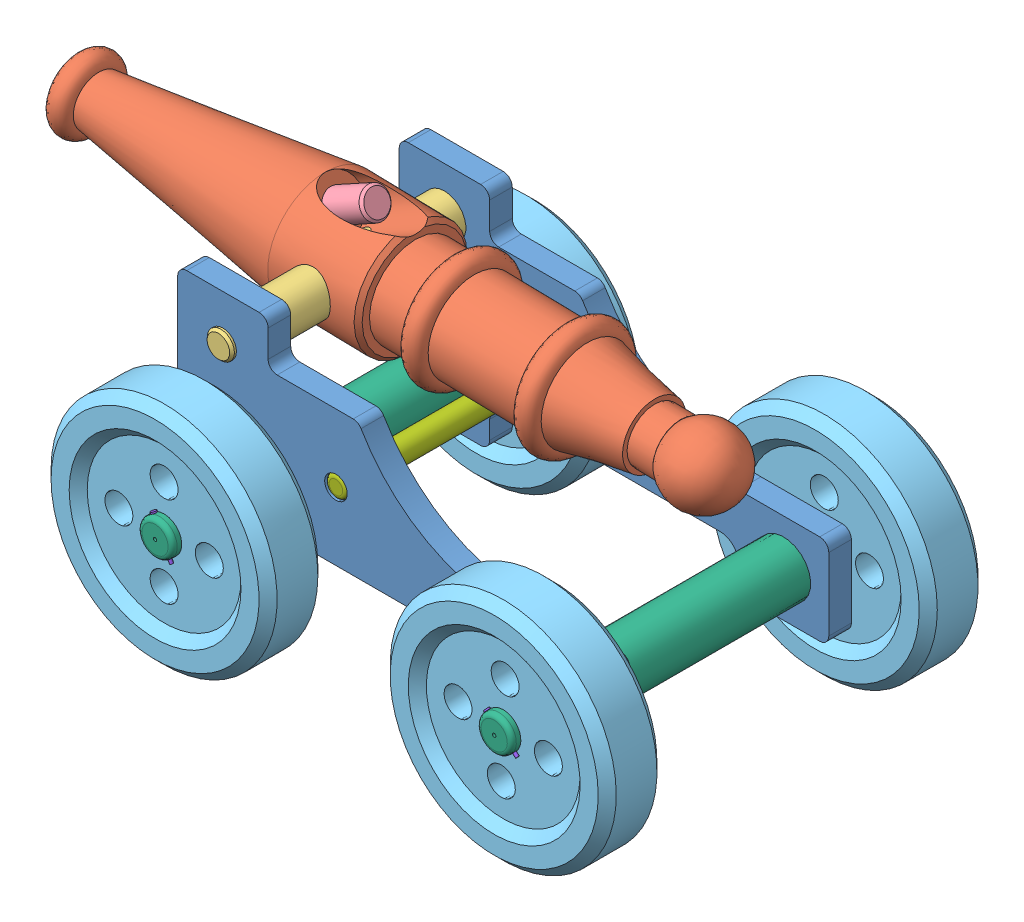
SolidWorks assembly Assem1, configuration Varsayılan. Lengths in mm.
Overall size (1654.34 725.8 840).
16 component instances, 8 part files, 31 mates.
Components (placement in the parent):
- yan parçalar-1: yan parçalar [Varsayılan] at (-537.6086 -308.226 925) size (950 500 50)
- yan parçalar-2: yan parçalar [Varsayılan] at (-537.6086 -308.226 435) size (950 500 50)
- top-1: top [Varsayılan] at (-331.2218 -35.2403 660) x (0.999785 -0.020755 0) z (0 0 1) size (1470 298.28 279.51)
- destek parça 2-1: destek parça 2 [Varsayılan] at (-437.6086 61.774 425) x (0 0 1) z (-1 0 0) size (560 95 95)
- çivi 2-1: çivi 2 [Varsayılan] at (-509.6694 189.1829 637.3824) x (0.876216 0.481918 0) z (-0.34062 0.619311 0.707412) size (318 64 64)
- teker-1: teker [Varsayılan] at (312.3914 -67.237 -513.471) x (0 0 -1) z (-1 0 0) size (130 500 500)
- teker-2: teker [Varsayılan] at (-437.6086 -349.215 -513.471) x (0 0 -1) z (1 0 0) size (130 500 500)
- teker-3: teker [Varsayılan] at (-437.6086 -349.215 196.529) x (0 0 -1) z (1 0 0) size (130 500 500)
- teker-4: teker [Varsayılan] at (306.4081 -349.088 196.529) x (0 0 -1) z (0.999099 -0.042438 0) size (130 500 500)
- destek parça-1: destek parça [Varsayılan] at (294.464 -193.0498 1173.5551) x (0 0 -1) z (-0.646111 -0.763244 0) size (840 120 120)
- destek parça-2: destek parça [Varsayılan] at (-427.1025 -229.2338 1173.5551) x (0 0 -1) z (0.894391 0.447286 0) size (840 120 120)
- ara vida-1: ara vida [Varsayılan] at (-187.6086 -83.226 975) x (0 0 -1) z (1 0 0) size (540 50 50)
- çivi-1: çivi [Varsayılan] at (-456.4668 -170.6977 1104.0005) x (0.012037 0.00602 0.999909) z (0.89431 0.447246 -0.013459) size (12 90 12)
- çivi-2: çivi [Varsayılan] at (282.4363 -178.6073 305.0423) x (-0.350187 -0.413672 -0.840383) z (-0.542981 -0.641417 0.541992) size (12 90 12)
- çivi-3: çivi [Varsayılan] at (-454.4406 -169.6843 294.4119) x (-0.325669 -0.162868 0.931351) z (0.832991 0.41658 0.364124) size (12 90 12)
- çivi-4: çivi [Varsayılan] at (283.9475 -176.8222 1107.8221) x (-0.602044 -0.711188 0.362979) z (0.234525 0.277042 0.931797) size (12 90 12)
Mates (geometry in assembly coordinates):
- Eş Merkezli1: concentric anti-aligned: cylinder of top-1 through (-437.6086 91.774 520.2468) axis (0 0 1) radius 47.5; cylinder of destek parça 2-1 through (-437.6086 91.774 425) axis (0 0 -1) radius 47.5
- Çakışık1: coincident anti-aligned: plane of yan parçalar-1 through (-357.6086 171.774 925) normal (0 0 -1); plane of destek parça 2-1 through (-437.6086 121.774 925) normal (0 0 1)
- Eş Merkezli2: concentric aligned: cylinder of yan parçalar-1 through (-437.6086 91.774 975) axis (0 0 -1) radius 30; cylinder of destek parça 2-1 through (-437.6086 91.774 425) axis (0 0 -1) radius 30
- Eş Merkezli3: concentric aligned: cylinder of yan parçalar-2 through (-437.6086 91.774 485) axis (0 0 -1) radius 30; cylinder of destek parça 2-1 through (-437.6086 91.774 425) axis (0 0 -1) radius 30
- Çakışık2: coincident anti-aligned: plane of yan parçalar-2 through (-357.6086 171.774 485) normal (0 0 1); plane of destek parça 2-1 through (-437.6086 121.774 485) normal (0 0 -1)
- Eş Merkezli4: concentric aligned: cylinder of top-1 through (-632.0621 96.0319 660) axis (-0.876216 -0.481918 0) radius 16; cylinder of çivi 2-1 through (-689.7753 64.2898 660) axis (-0.876216 -0.481918 0) radius 16
- Çakışık3: coincident anti-aligned: plane of top-1 through (-506.4708 183.3673 660) normal (0.876216 0.481918 0); plane of çivi 2-1 through (-509.6694 189.1829 637.3824) normal (-0.876216 -0.481918 0)
- Eş Merkezli6: concentric anti-aligned: cylinder of yan parçalar-2 through (312.3914 -208.226 485) axis (0 0 -1) radius 40; cylinder of destek parça-1 through (312.3914 -208.226 1125) axis (0 0 1) radius 39
- Eş Merkezli7: concentric anti-aligned: cylinder of yan parçalar-1 through (312.3914 -208.226 975) axis (0 0 -1) radius 40; cylinder of destek parça-1 through (312.3914 -208.226 1125) axis (0 0 1) radius 39
- Çakışık4: coincident anti-aligned: plane of yan parçalar-1 through (-357.6086 171.774 925) normal (0 0 -1); plane of destek parça-1 through (343.6844 -234.7165 925) normal (0 0 1)
- Eş Merkezli8: concentric aligned: cylinder of teker-1 through (312.3914 -208.226 285) axis (0 0 1) radius 39; cylinder of destek parça-1 through (312.3914 -208.226 1125) axis (0 0 1) radius 39
- Eş Merkezli9: concentric aligned: cylinder of teker-4 through (312.3914 -208.226 995) axis (0 0 1) radius 39; cylinder of destek parça-1 through (312.3914 -208.226 1125) axis (0 0 1) radius 39
- Çakışık5: coincident anti-aligned: plane of teker-4 through (319.606 -38.3791 1015) normal (0 0 -1); plane of destek parça-1 through (343.6844 -234.7165 1015) normal (0 0 1)
- Çakışık7: coincident anti-aligned: plane of teker-1 through (312.3914 -378.226 395) normal (0 0 1); plane of destek parça-1 through (343.6844 -234.7165 395) normal (0 0 -1)
- Eş Merkezli10: concentric anti-aligned: cylinder of yan parçalar-1 through (-437.6086 -208.226 975) axis (0 0 -1) radius 30; cylinder of destek parça-2 through (-437.6086 -208.226 1125) axis (0 0 1) radius 39
- Eş Merkezli11: concentric anti-aligned: cylinder of yan parçalar-2 through (-437.6086 -208.226 485) axis (0 0 -1) radius 30; cylinder of destek parça-2 through (-437.6086 -208.226 1125) axis (0 0 1) radius 39
- Çakışık8: coincident anti-aligned: plane of yan parçalar-1 through (-357.6086 171.774 925) normal (0 0 -1); plane of destek parça-2 through (-455.9473 -171.5559 925) normal (0 0 1)
- Eş Merkezli12: concentric aligned: cylinder of teker-2 through (-437.6086 -208.226 285) axis (0 0 1) radius 39; cylinder of destek parça-2 through (-437.6086 -208.226 1125) axis (0 0 1) radius 39
- Çakışık9: coincident anti-aligned: plane of teker-2 through (-437.6086 -38.226 395) normal (0 0 1); plane of destek parça-2 through (-455.9473 -171.5559 395) normal (0 0 -1)
- Eş Merkezli13: concentric aligned: cylinder of teker-3 through (-437.6086 -208.226 995) axis (0 0 1) radius 39; cylinder of destek parça-2 through (-437.6086 -208.226 1125) axis (0 0 1) radius 39
- Çakışık10: coincident anti-aligned: plane of teker-3 through (-437.6086 -38.226 1015) normal (0 0 -1); plane of destek parça-2 through (-455.9473 -171.5559 1015) normal (0 0 1)
- Eş Merkezli14: concentric anti-aligned: cylinder of yan parçalar-1 through (-187.6086 -58.226 975) axis (0 0 -1) radius 25; cylinder of ara vida-1 through (-187.6086 -58.226 975) axis (0 0 1) radius 25
- Çakışık11: coincident aligned: plane of yan parçalar-2 through (-357.6086 171.774 435) normal (0 0 -1); plane of ara vida-1 through (-187.6086 -58.226 435) normal (0 0 -1)
- Eş Merkezli16: concentric anti-aligned: cylinder of destek parça-2 through (-410.7714 -261.8894 1110) axis (-0.447286 0.894391 0) radius 3.5; cylinder of çivi-1 through (-416.1388 -251.1567 1110) axis (0.447286 -0.894391 0) radius 3.5
- Teğet2: tangent anti-aligned: cylinder of destek parça-2 through (-437.6086 -208.226 1125) axis (0 0 1) radius 39; plane of çivi-1 through (-455.0106 -173.3237 1113.4997) normal (0.447286 -0.894391 0)
- Eş Merkezli18: concentric anti-aligned: cylinder of destek parça-2 through (-410.7714 -261.8894 300) axis (-0.447286 0.894391 0) radius 3.5; cylinder of çivi-3 through (-416.1388 -251.1567 300) axis (0.447286 -0.894391 0) radius 3.5
- Teğet4: tangent anti-aligned: cylinder of destek parça-2 through (-437.6086 -208.226 1125) axis (0 0 1) radius 39; plane of çivi-3 through (-456.1926 -173.9148 303.2597) normal (0.447286 -0.894391 0)
- Eş Merkezli19: concentric aligned: cylinder of destek parça-1 through (266.5968 -169.4593 300) axis (0.763244 -0.646111 0) radius 3.5; cylinder of çivi-2 through (349.0271 -239.2393 300) axis (0.763244 -0.646111 0) radius 3.5
- Teğet5: tangent anti-aligned: cylinder of destek parça-1 through (312.3914 -208.226 1125) axis (0 0 1) radius 39; plane of çivi-2 through (281.3993 -184.4755 297.0587) normal (0.763244 -0.646111 0)
- Eş Merkezli20: concentric aligned: cylinder of destek parça-1 through (266.5968 -169.4593 1110) axis (0.763244 -0.646111 0) radius 3.5; cylinder of çivi-4 through (349.0271 -239.2393 1110) axis (0.763244 -0.646111 0) radius 3.5
- Teğet6: tangent anti-aligned: cylinder of destek parça-1 through (312.3914 -208.226 1125) axis (0 0 1) radius 39; plane of çivi-4 through (280.5178 -185.5168 1111.2704) normal (0.763244 -0.646111 0)
